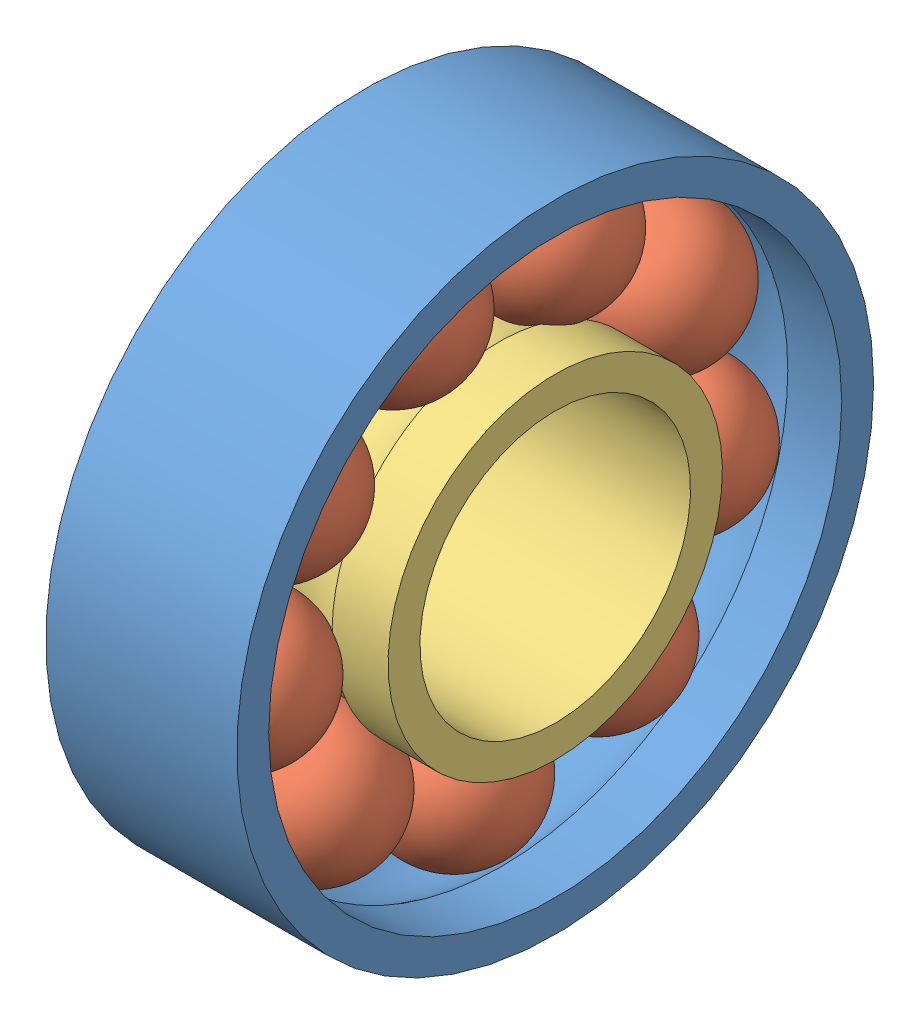
SolidWorks assembly 轴承(D40d17B12), configuration 默认. Lengths in mm.
Overall size (12 40 40).
11 component instances, 3 part files, 2 mates.
Components (placement in the parent):
- 轴承外圈-1: 轴承外圈 [默认] at (-38.3167 -0.6276 23.4958) size (12 40 40)
- 轴承球-1: 轴承球 [默认] at (-38.2219 -28.7939 23.9862) size (9 9 9)
- 轴承球-2: 轴承球 [默认] at (-38.2219 -25.8533 14.9261) x (1 0 0) z (0 -0.642788 0.766044) size (9 9 9)
- 轴承球-3: 轴承球 [默认] at (-38.2219 -17.777 9.876) x (1 0 0) z (0 -0.984808 0.173648) size (9 9 9)
- 轴承球-4: 轴承球 [默认] at (-38.2219 -8.344 11.1987) x (1 0 0) z (0 -0.866025 -0.5) size (9 9 9)
- 轴承球-5: 轴承球 [默认] at (-38.2219 -1.9681 18.2753) x (1 0 0) z (0 -0.34202 -0.939693) size (9 9 9)
- 轴承球-6: 轴承球 [默认] at (-38.2219 -1.6327 27.7947) x (1 0 0) z (0 0.34202 -0.939693) size (9 9 9)
- 轴承球-7: 轴承球 [默认] at (-38.2219 -7.4947 35.3026) x (1 0 0) z (0 0.866025 -0.5) size (9 9 9)
- 轴承球-8: 轴承球 [默认] at (-38.2219 -16.8112 37.2859) x (1 0 0) z (0 0.984808 0.173648) size (9 9 9)
- 轴承球-9: 轴承球 [默认] at (-38.2219 -25.2229 32.8167) x (1 0 0) z (0 0.642788 0.766044) size (9 9 9)
- 轴承内圈-4: 轴承内圈 [默认] at (-38.3167 -4.5391 33.3029) x (1 0 0) z (0 -0.68822 0.725502) size (12 21 21)
Mates (geometry in assembly coordinates):
- 重合1: coincident: plane of 轴承外圈-1 through (-44.3167 3.1224 23.4958) normal (-1 0 0); plane of 轴承内圈-4 through (-44.3167 -8.7108 29.3457) normal (-1 0 0)
- 同心1: concentric: circle of 轴承外圈-1; circle of 轴承内圈-4
